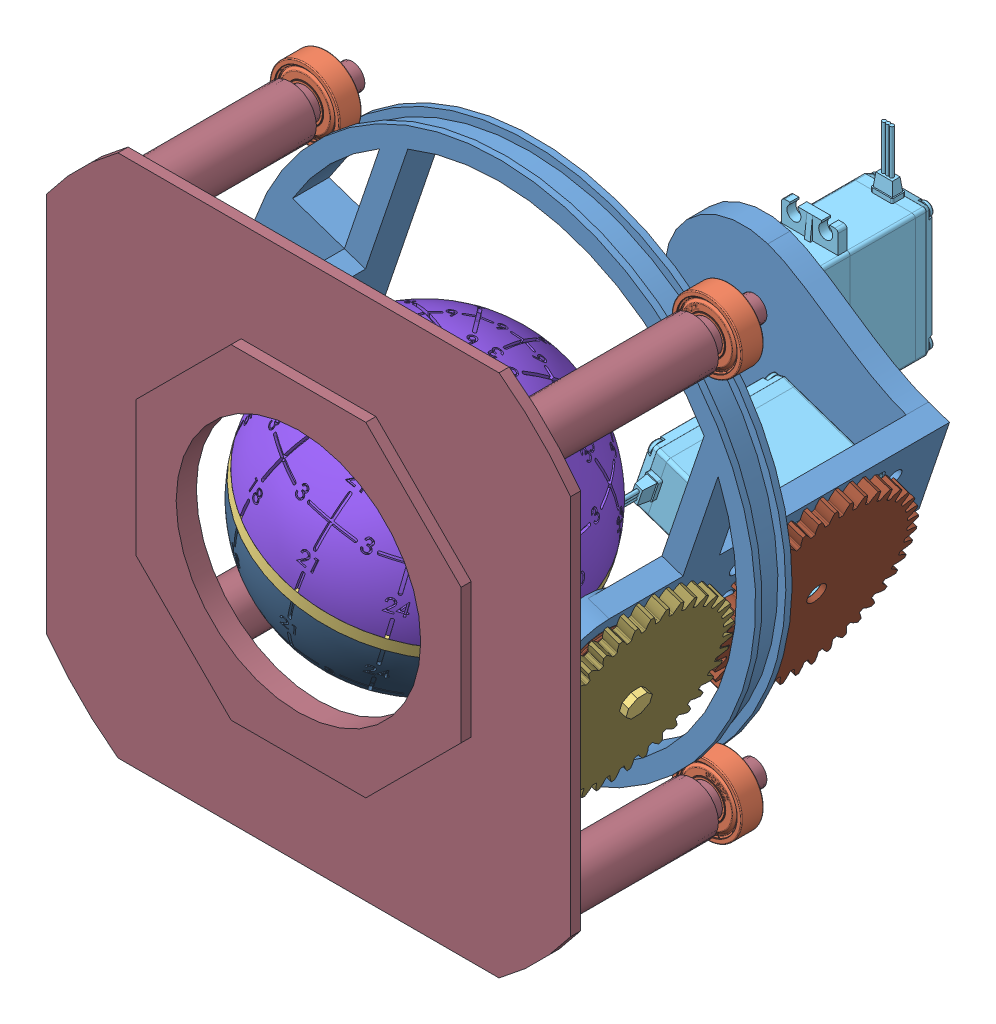
SolidWorks assembly Roll, configuration Default. Lengths in mm.
Overall size (205.36 205.36 211.91).
23 component instances, 13 part files, 7 mates.
Components (placement in the parent):
- Pitch2-1: Pitch2 [Default] at (-0.9315 -1.3254 -3.1099) x (0.947303 -0.320338 0) z (0 0 1) size (162 162 168.07)
  - PitchBracketV2-1: PitchBracketV2 [Default] at origin size (162 162 121.57)
  - Ball Bearing 608ZZ-2: Ball Bearing 608ZZ [Défaut] at (-52.75 0 -1.875) x (0 0 -1) z (-1 0 0) size (22 22 7)
  - Ball Bearing 608ZZ-3: Ball Bearing 608ZZ [Défaut] at (52.75 0 -1.875) x (0 0 -1) z (1 0 0) size (22 22 7)
  - Yaw-1: Yaw [Default] at (-53.019 -60.801 -96.8449) x (1 0 0) z (0 -0.046911 0.998899) size (130.2 88.9 117.86)
    - BallPlate-1: BallPlate [Default] at (53.019 65.1893 92.0131) size (127.54 8 88.9)
    - SKF 625-1: SKF 625 [Default] at (53.019 62.6893 92.0131) x (0 1 0) z (-0.440998 0 0.897508) size (5 16 16)
    - Servo-1: Servo [noHorn] at (53.019 67.1893 71.9881) x (0 0 -1) z (1 0 0) size (19.8 47.23 67)
    - YawServoGear-1: YawServoGear [Default] at (42.719 84.6893 71.9881) x (-0.590306 0 0.80718) z (0 -1 0) size (24.43 24.43 4)
    - BallShaft_V2-1: BallShaft_V2 [Default] at (53.019 65.1893 92.0131) x (-0.986105 0 0.166123) z (-0.166123 0 -0.986105) size (24.43 75.9 24.43)
    - Ball_V9.1_Top-1: Ball_V9.1_Top [Default] at (53.019 65.1893 92.0131) x (-0.907868 0 -0.419257) z (0.419257 0 -0.907868) size (88.8 42.45 88.81)
    - socket head cap screw_am-1: socket head cap screw_am [B18.3.1M - 3 x 0.5 x 20 Hex SHCS -- 20SHX] at (53.019 108.6393 92.0131) x (0 -1 0) z (0 0 1) size (23 5.5 5.5)
    - Ball_V9.1_Bot-1: Ball_V9.1_Bot [Default] at (53.019 65.1893 92.0131) x (-0.907868 0 -0.419257) z (0.419257 0 -0.907868) size (88.8 87.56 88.81)
    - socket head cap screw_am-2: socket head cap screw_am [B18.3.1M - 3 x 0.5 x 20 Hex SHCS -- 20SHX] at (53.019 21.7393 92.0131) x (0 1 0) z (0.546944 0 -0.837169) size (23 5.5 5.5)
  - Servo-1: Servo [Default] at (47.25 0 -70.05) x (0 1 0) z (0 0 -1) size (19.8 47.23 67)
  - PitchServoGear-1: PitchServoGear [Default] at (69.15 0 -59.75) x (0 -0.80252 -0.596625) z (-1 0 0) size (60.99 60.99 5)
  - PitchGear-1: PitchGear [Default] at (64.15 0 -1.875) x (0 0.061118 -0.998131) z (1 0 0) size (60.99 60.99 12.6)
- FrontFace-1: FrontFace [Default] at (-0.9315 -1.3254 28.4312) size (165 165 80.2)
- Ball Bearing 608ZZ-1: Ball Bearing 608ZZ [Défaut] at (62.3546 61.9607 -33.9224) x (0.998025 0.062819 0) z (0 0 1) size (22 22 7)
- Ball Bearing 608ZZ-2: Ball Bearing 608ZZ [Défaut] at (62.3546 -64.6115 -33.9224) x (0.062819 -0.998025 0) z (0 0 1) size (22 22 7)
- Ball Bearing 608ZZ-3: Ball Bearing 608ZZ [Défaut] at (-64.2176 -64.6115 -33.9224) x (-0.998025 -0.062819 0) z (0 0 1) size (22 22 7)
- Ball Bearing 608ZZ-4: Ball Bearing 608ZZ [Défaut] at (-64.2176 61.9607 -33.9224) x (-0.062819 0.998025 0) z (0 0 1) size (22 22 7)
- Servo-1: Servo [Default] at (-0.9315 -11.6254 -129.0099) x (1 0 0) z (0 -1 0) size (19.8 47.23 67)
Mates (geometry in assembly coordinates):
- Concentric1: concentric: circle of FrontFace-1; circle of Pitch2-1/PitchBracketV2-1
- Distance2: distance = 56.6036 mm: plane of Pitch2-1/PitchBracketV2-1 through (71.6709 59.6304 -28.1724) normal (0 0 1); plane of FrontFace-1 through (-0.9315 -1.3254 28.4312) normal (0 0 -1)
- Width1: width: plane of Pitch2-1/PitchBracketV2-1 through (71.6709 59.6304 -28.1724) normal (0 0 1); plane of Pitch2-1/PitchBracketV2-1 through (71.6709 59.6304 -39.6724) normal (0 0 -1); plane of Ball Bearing 608ZZ-1 through (62.3546 61.9607 -37.4224) normal (0 0 -1); plane of Ball Bearing 608ZZ-1 through (62.3546 61.9607 -30.4224) normal (0 0 1)
- Tangent1: tangent: cylinder of Ball Bearing 608ZZ-1 through (62.3546 61.9607 201.1279) axis (0 0 1) radius 11; cylinder of Pitch2-1/PitchBracketV2-1 through (-0.9315 -1.3254 -37.6724) axis (0 0 1) radius 78.5
- Parallel1: parallel: plane of FrontFace-1 through (-0.9315 100.6485 31.6062) normal (0 1 0); plane of assembly through (0 72.9607 0) normal (0 1 0)
- Coincident2: coincident: plane of Pitch2-1/PitchBracketV2-1 through (-0.9315 -1.3254 -109.1099) normal (0 0 -1); plane of Servo-1 through (-0.9315 -1.3254 -109.1099) normal (0 0 1)
- Concentric2: concentric: circle of Pitch2-1/PitchBracketV2-1; circle of Servo-1
